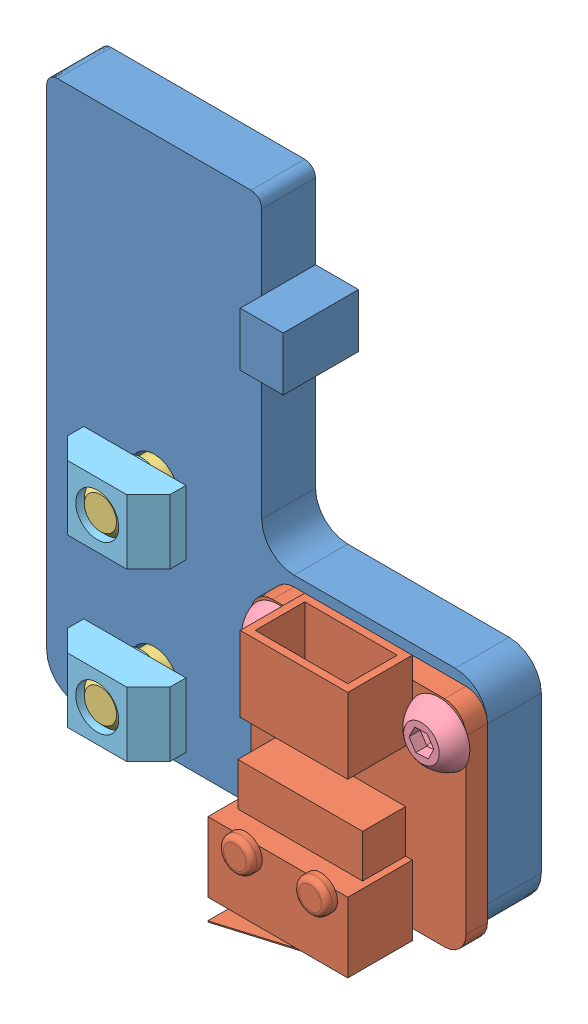
SolidWorks assembly ASM Z-Axis Limit Switch, configuration Standard. Lengths in mm.
Overall size (42.55 53.95 18).
8 component instances, 5 part files, 20 mates.
Components (placement in the parent):
- Z limit switch bracket-1: Z limit switch bracket [Standard] at origin size (41 49.5 7)
- limit switch-1: limit switch [Standard] at (10.5 -0.95 5) x (0 1 0) z (0 0 1) size (26 20 11)
- M4X10 Socket Head Screw-1: M4X10 Socket Head Screw [Standard] at (-10.5 -4.5 0) x (0 0 1) z (1 0 0) size (14 6.8 6.8)
- M4X10 Socket Head Screw-2: M4X10 Socket Head Screw [Standard] at (-10.5 11 0) x (0 0 1) z (0.987351 0.158553 0) size (14 6.8 6.8)
- M3X6Pan Head Screw-1: M3X6Pan Head Screw [Standard] at (18 6.05 8.65) x (0 0 -1) z (0.452415 0.891807 0) size (8.15 6.02 6.02)
- M3X6Pan Head Screw-2: M3X6Pan Head Screw [Standard] at (3 6.05 8.65) x (0 0 -1) z (0.066884 0.997761 0) size (8.15 6.02 6.02)
- M4 T-Slot Nut-1: M4 T-Slot Nut [Standard] at (-10.5 -4.5 7.6373) x (0 1 0) z (0 0 1) size (6 9.5 4.1)
- M4 T-Slot Nut-2: M4 T-Slot Nut [Standard] at (-10.5 11 7.6373) x (0 1 0) z (0 0 1) size (6 9.5 4.1)
Mates (geometry in assembly coordinates):
- Konzentrisch96: concentric: cylinder of Z limit switch bracket-1 through (0.1837 6.05 -0.5012) axis (0 0 1) radius 1.45; cylinder of limit switch-1 through (0.1837 6.05 4.8) axis (0 0 1) radius 1.55
- Konzentrisch97: concentric: cylinder of Z limit switch bracket-1 through (-14.8163 6.05 -0.5012) axis (0 0 1) radius 1.45; cylinder of limit switch-1 through (-14.8163 6.05 4.8) axis (0 0 1) radius 1.55
- Deckungsgleich108: coincident: plane of Z limit switch bracket-1 through (6.7849 43.9512 5) normal (0 0 1); plane of limit switch-1 through (-7.3163 -0.95 5) normal (0 0 -1)
- Konzentrisch98: concentric: cylinder of Z limit switch bracket-1 through (-28.3163 -4.5 -0.5012) axis (0 0 1) radius 2.25; cylinder of M4X10 Socket Head Screw-1 through (-28.3163 -4.5 -0.9416) axis (0 0 -1) radius 2
- Deckungsgleich109: coincident: plane of Z limit switch bracket-1 through (6.7849 43.9512 0) normal (0 0 -1); plane of M4X10 Socket Head Screw-1 through (-28.3163 -7.9 0) normal (0 0 1)
- Konzentrisch99: concentric: cylinder of Z limit switch bracket-1 through (-28.3163 11 -0.5012) axis (0 0 1) radius 2.25; cylinder of M4X10 Socket Head Screw-2 through (-28.3163 11 -0.9416) axis (0 0 -1) radius 2
- Deckungsgleich110: coincident: plane of Z limit switch bracket-1 through (6.7849 43.9512 0) normal (0 0 -1); plane of M4X10 Socket Head Screw-2 through (-27.7772 7.643 0) normal (0 0 1)
- Konzentrisch113: concentric: cylinder of Z limit switch bracket-1 through (-28.3163 -4.5 -0.5012) axis (0 0 1) radius 2.25; cylinder of M4 T-Slot Nut-1 through (-28.3163 -4.5 10.5663) axis (0 0 -1) radius 2
- Konzentrisch114: concentric: cylinder of Z limit switch bracket-1 through (-28.3163 11 -0.5012) axis (0 0 1) radius 2.25; cylinder of M4 T-Slot Nut-2 through (-28.3163 11 10.5663) axis (0 0 -1) radius 2
- Konzentrisch100: concentric: cylinder of limit switch-1 through (0.1837 6.05 4.8) axis (0 0 1) radius 1.55; cylinder of M3X6Pan Head Screw-1 through (0.1837 6.05 1) axis (0 0 1) radius 1.5
- Deckungsgleich111: coincident: plane of limit switch-1 through (-7.3163 -0.95 7) normal (0 0 1); plane of M3X6Pan Head Screw-1 through (0.1837 6.05 7) normal (0 0 -1)
- Konzentrisch101: concentric: cylinder of limit switch-1 through (-14.8163 6.05 4.8) axis (0 0 1) radius 1.55; cylinder of M3X6Pan Head Screw-2 through (-14.8163 6.05 1) axis (0 0 1) radius 1.5
- Deckungsgleich112: coincident: plane of limit switch-1 through (-7.3163 -0.95 7) normal (0 0 1); plane of M3X6Pan Head Screw-2 through (-14.8163 6.05 7) normal (0 0 -1)
- Parallel1: parallel: plane of Z limit switch bracket-1 through (-17.5151 39 -0.5012) normal (0 1 0); plane of M4 T-Slot Nut-2 through (-28.3163 14 7.6373) normal (0 1 0)
- Parallel2: parallel: plane of M4 T-Slot Nut-1 through (-28.3163 -1.5 7.6373) normal (0 1 0); plane of M4 T-Slot Nut-2 through (-28.3163 14 7.6373) normal (0 1 0)
- Abstand1: distance = 1.8 mm: plane of M4 T-Slot Nut-2 through (-5.75 14 6.8) normal (0 0 -1); plane of Z limit switch bracket-1 through (24.6012 43.9512 5) normal (0 0 1)
- Deckungsgleich113: coincident: plane of M4 T-Slot Nut-1 through (-23.5663 -1.5 6.8) normal (0 0 -1); plane of M4 T-Slot Nut-2 through (-23.5663 14 6.8) normal (0 0 -1)
- Deckungsgleich114: coincident: plane of Z limit switch bracket-1 through (-17.8163 0 0) normal (0 0 1); plane of assembly through (0 0 0) normal (0 0 1)
- Deckungsgleich115: coincident: plane of Z limit switch bracket-1 through (-17.8163 0 0) normal (0 1 0); plane of assembly through (0 0 0) normal (0 1 0)
- Deckungsgleich116: coincident: plane of Z limit switch bracket-1 through (0 0 0) normal (1 0 0); plane of assembly through (0 0 0) normal (1 0 0)
